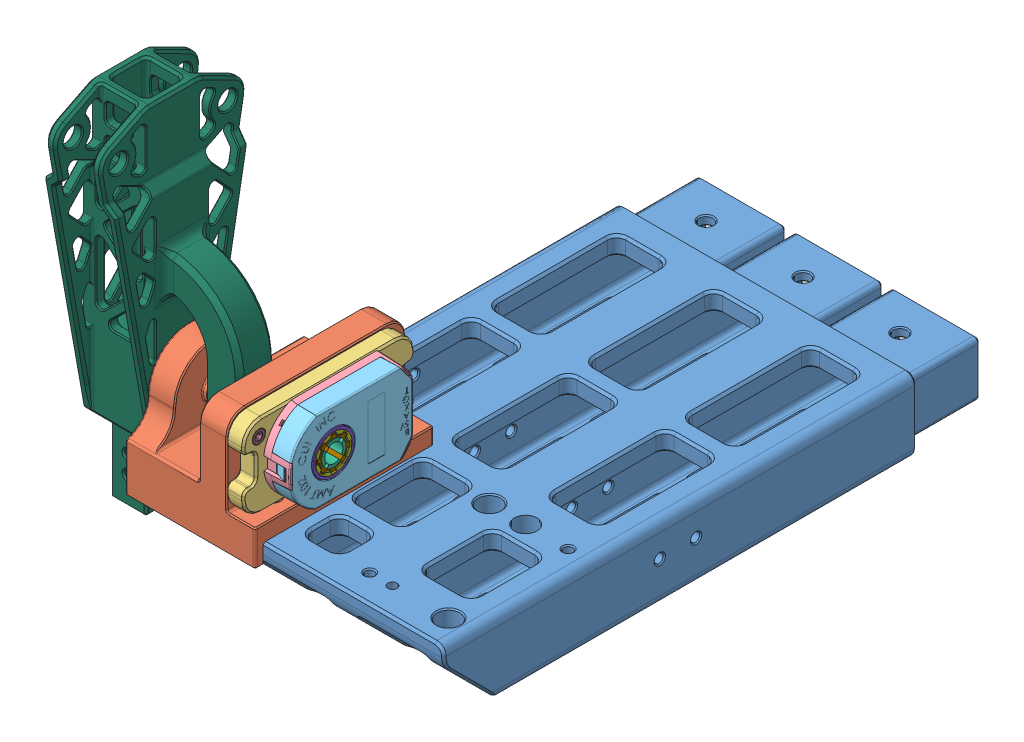
SolidWorks assembly 53+56+57+SlabAssembly, configuration Default. Lengths in mm.
Overall size (135.64 127 196.98).
20 component instances, 15 part files, 5 mates.
Components (placement in the parent):
- AARL_Puppy_18_01_01_057-1: AARL_Puppy_18_01_01_057 [Default] at (81.0166 87.201 161.9937) x (0 0 -1) z (1 0 0) size (190.5 25.4 104.78)
- 56+57+SlabAssembly-1: 56+57+SlabAssembly [Default] at (-61.8053 -8.053 232.2066) x (0 0 -1) z (1 0 0) size (63.21 45.01 52.32)
  - AARL_Puppy_18_01_01_056_R-1: AARL_Puppy_18_01_01_056_R [Default] at (-15.6391 107.954 87.1324) x (-1 0 0) z (0 0 -1) size (63.21 41.33 47.01)
  - Slab_Assembly-1: Slab_Assembly [Default] at (56.243 111.4195 68.7964) size (59.83 36.33 21.74)
    - AARL_Puppy_18_01_01_055-1: AARL_Puppy_18_01_01_055 [Default] at (-49.6698 17.0323 53.8961) x (0 1 0) z (0 0 1) size (28.78 59.83 10.72)
    - CUI_DEVICES_cui_devices_amt102-0048-i6350-s-1: CUI_DEVICES_cui_devices_amt102-0048-i6350-s [Default] at (-49.6698 17.0323 63.6859) x (0 1 0) z (0 0 1) size (36.33 46.23 9.15)
      - CUI_DEVICES_amt-102-base-rev-k-1: CUI_DEVICES_amt-102-base-rev-k [Default] x (-1 0 0) z (0 0 -1) size (28.83 43.41 9.03)
      - CUI_DEVICES_amt-102-top-cover-rev-h-1: CUI_DEVICES_amt-102-top-cover-rev-h [Default] at (0 0 5.23) x (-1 0 0) z (0 0 -1) size (28.6 43.26 6.55)
      - CUI_DEVICES_amt-sleeve-rev-d(d)-1: CUI_DEVICES_amt-sleeve-rev-d(d) [Default] at (0 0 -2.42) x (0.999996 0.002864 0) z (0 0 1) size (10.79 10.79 7.8)
      - CUI_DEVICES_amt-hub-top-rev-d1-1: CUI_DEVICES_amt-hub-top-rev-d1 [Default] at (0 0 2.13) x (0.999996 0.002864 0) z (0 0 1) size (14 14 5.67)
      - CUI_DEVICES_amt-hub-bottom-rev-b-1: CUI_DEVICES_amt-hub-bottom-rev-b [Default] at (0 0 2.43) x (0.999998 -0.001942 0) z (0 0 1) size (17.3 17.3 3.2)
      - CUI_DEVICES_amt10x-shaft-adaptor-rev-e-1: CUI_DEVICES_amt10x-shaft-adaptor-rev-e [Default] at (0 0 0.03) x (0.999996 0.002864 0) z (0 0 1) size (11.8 11.8 7.8)
      - CUI_DEVICES_receiver-board-1: CUI_DEVICES_receiver-board [Default] at (72.2834 -20.351 3.03) x (-1 0 0) z (0 0 -1) size (26.5 26.62 0.41)
      - CUI_DEVICES_rotor-board-rev f-1: CUI_DEVICES_rotor-board-rev f [Default] at (0 0 2.13) x (0.807874 -0.589355 0) z (0 0 1) size (26 26 0.3)
      - CUI_DEVICES_transmitter-board amt10(amt-102)-1: CUI_DEVICES_transmitter-board amt10(amt-102) [Default] at (19.1596 -17.1102 1.22) x (-1 0 0) z (0 0 -1) size (26.63 38.43 4.41)
    - AARL_Puppy_18_04_01_017-2: AARL_Puppy_18_04_01_017 [Default] at (-66.6525 25.9223 59.9159) x (0.971112 0.238624 0) z (-0.238624 0.971112 0) size (4.65 12.57 4.65)
    - AARL_Puppy_18_04_01_017-3: AARL_Puppy_18_04_01_017 [Default] at (-17.8182 8.1423 59.8989) x (0.719542 0.694449 0) z (-0.694449 0.719542 0) size (4.65 12.57 4.65)
  - 6377K310_ULTRA-LOW-FRICTION DRY-RUNNING SLEEVE BEARING-1: 6377K310_ULTRA-LOW-FRICTION DRY-RUNNING SLEEVE BEARING [6377K31] at (6.5859 128.4518 90.3074) x (0.990875 0.134785 0) z (0 0 1) size (9.55 9.55 6.35)
  - 6377K310_ULTRA-LOW-FRICTION DRY-RUNNING SLEEVE BEARING-2: 6377K310_ULTRA-LOW-FRICTION DRY-RUNNING SLEEVE BEARING [6377K31] at (6.5859 128.4518 119.5174) size (9.55 9.55 6.35)
- AARL_Puppy_18_01_02_050-1: AARL_Puppy_18_01_02_050 [Default] at (10.4681 137.8613 225.6207) size (51.69 127 50.8)
Mates (geometry in assembly coordinates):
- Coincident1: coincident anti-aligned: plane of AARL_Puppy_18_01_01_057-1 through (81.0166 99.901 79.4437) normal (0 1 0); plane of 56+57+SlabAssembly-1/AARL_Puppy_18_01_01_056_R-1 through (25.3271 99.901 185.4252) normal (0 -1 0)
- Concentric1: concentric aligned: cylinder of AARL_Puppy_18_01_01_057-1 through (36.5666 82.3256 235.0187) axis (0 1 0) radius 3.9688; cylinder of 56+57+SlabAssembly-1/AARL_Puppy_18_01_01_056_R-1 through (36.5666 93.551 235.0187) axis (0 1 0) radius 3.8418
- Parallel1: parallel aligned: plane of AARL_Puppy_18_01_01_057-1 through (28.6291 87.201 79.4437) normal (-1 0 0); plane of 56+57+SlabAssembly-1/AARL_Puppy_18_01_01_056_R-1 through (25.3271 134.8768 185.4252) normal (-1 0 0)
- Concentric2: concentric anti-aligned: cylinder of 56+57+SlabAssembly-1/AARL_Puppy_18_01_01_056_R-1 through (70.7508 120.3988 225.6207) axis (-1 0 0) radius 3.2385; cylinder of AARL_Puppy_18_01_02_050-1 through (-2.2319 120.3988 225.6207) axis (1 0 0) radius 3.2385
- Coincident4: coincident aligned: plane of 56+57+SlabAssembly-1/AARL_Puppy_18_01_01_056_R-1 through (43.1071 99.901 247.8457) normal (1 0 0); plane of AARL_Puppy_18_01_02_050-1 through (43.1071 137.8613 225.6207) normal (1 0 0)
